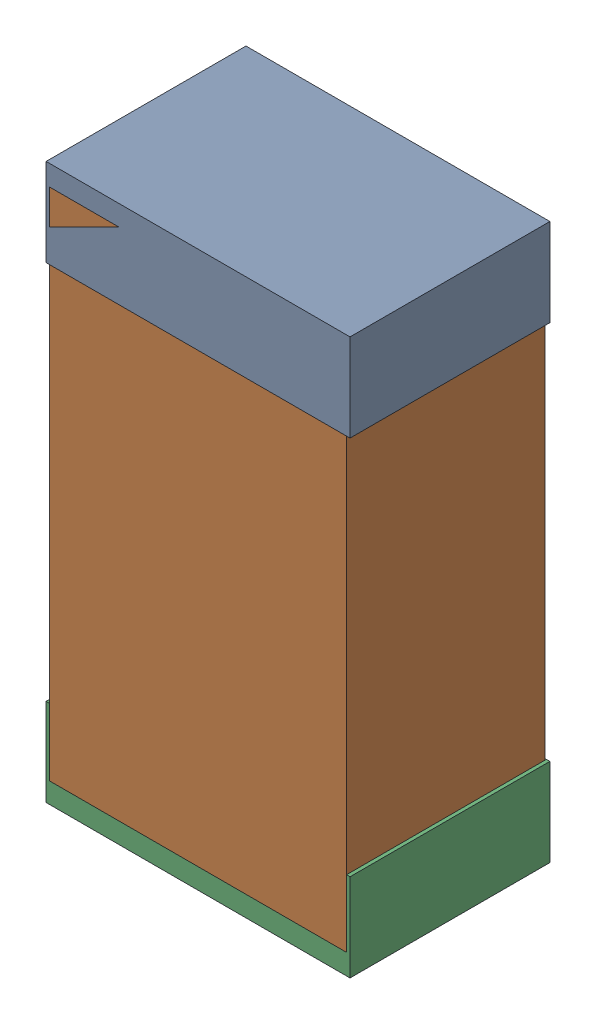
SolidWorks assembly R29Kanaloa_v2.0.0_Motor, configuration Default. Lengths in mm.
Overall size (1.3 2.38 0.85).
6 component instances, 2 part files, 0 mates.
Components (placement in the parent):
- 330415056-1: 330415056 [Default] at (81.788 94.98 -1.9574) size (1.3 0.38 0.85)
  - Extruded_2-1: Extruded_2 [Default] at origin size (1.3 0.38 0.85)
- 334787376-1: 334787376 [Default] at (81.788 93.98 -1.9524) size (1.27 2.2 0.85)
  - Extruded_16-1: Extruded_16 [Default] at origin size (1.27 2.2 0.85)
- 330415056-2: 330415056 [Default] at (81.788 92.98 -1.9574) size (1.3 0.38 0.85)
  - Extruded_2-1: Extruded_2 [Default] at origin size (1.3 0.38 0.85)
